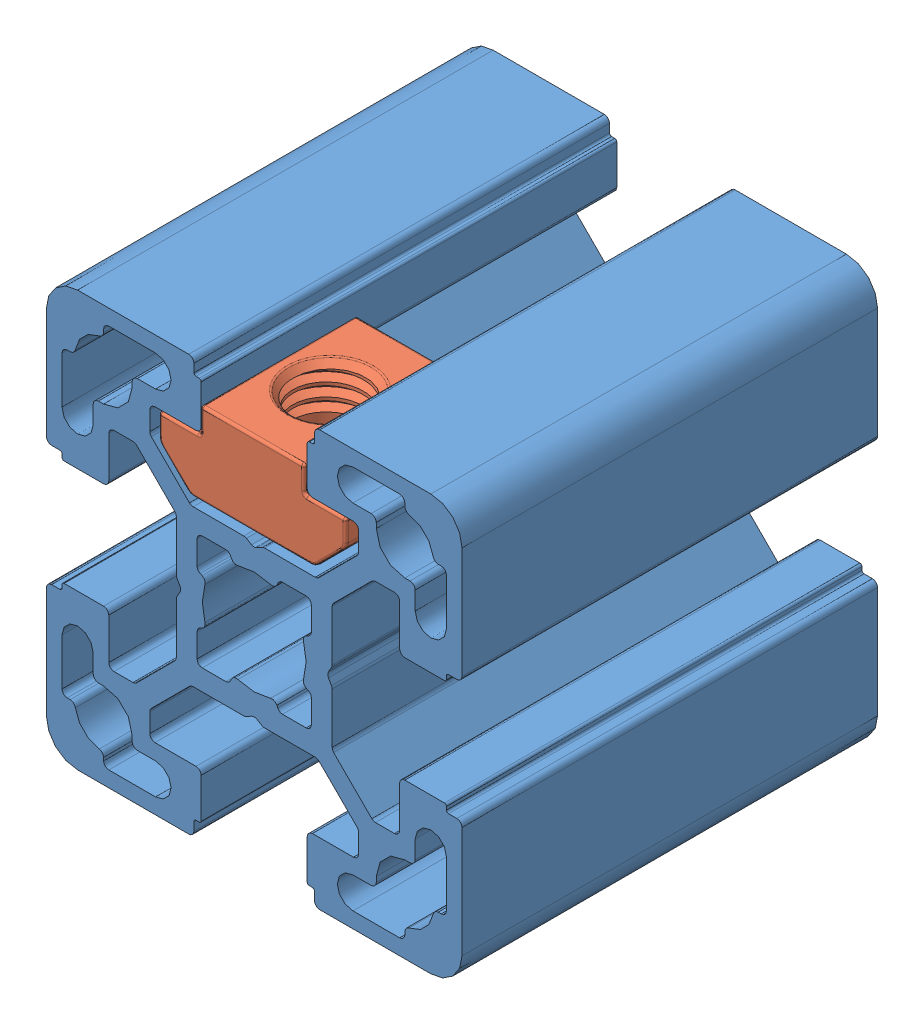
SolidWorks assembly Сборка Т-Сухарт 10 паз, configuration По умолчанию. Lengths in mm.
Overall size (40 40 40.19).
2 component instances, 2 part files, 2 mates.
Components (placement in the parent):
- 40х40-1: 40х40 [По умолчанию] at origin size (40 40 40)
- Т-Сухарь паз 10-1: Т-Сухарь паз 10 [По умолчанию] at (0 8.5 32.6946) size (18 8 15)
Mates (geometry in assembly coordinates):
- Совпадение1: coincident anti-aligned: plane of 40х40-1 through (0 14 40) normal (0 -1 0); plane of Т-Сухарь паз 10-1 through (-9 14 25.1946) normal (0 1 0)
- Расстояние1: distance = 0.1 mm anti-aligned: plane of 40х40-1 through (-5.1 0 40) normal (1 0 0); plane of Т-Сухарь паз 10-1 through (-5 14 25.1946) normal (-1 0 0)
